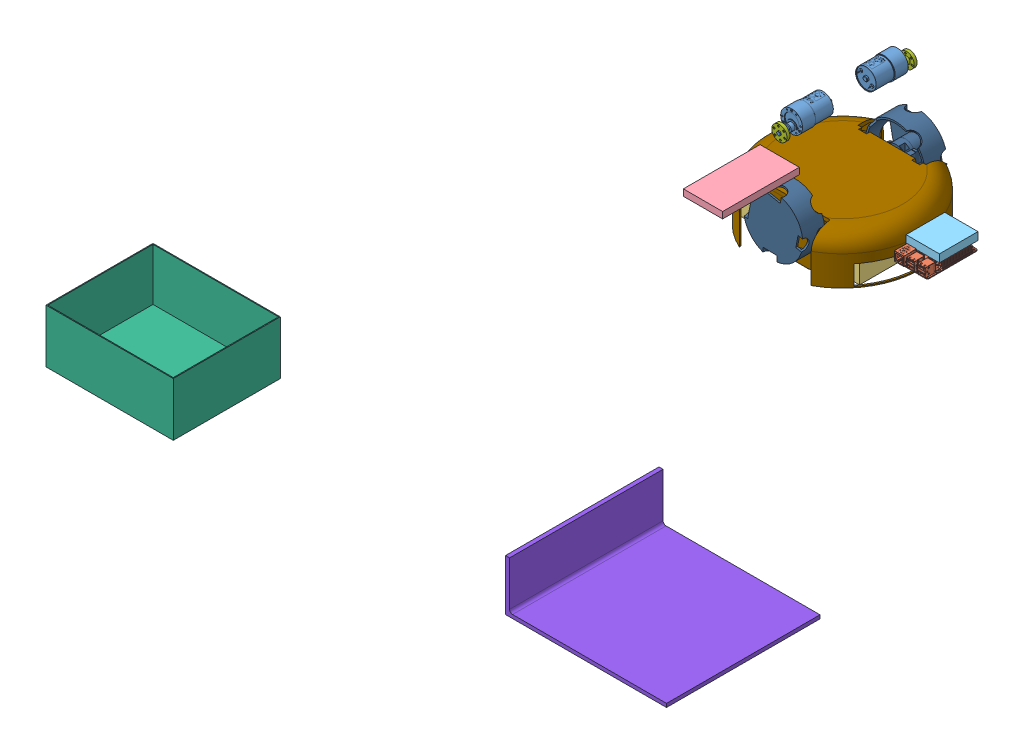
SolidWorks assembly BodyWithTwoWheels, configuration Default. Lengths in mm.
Overall size (403.59 568.25 671.49).
14 component instances, 11 part files, 40 mates.
Components (placement in the parent):
- Pololu37DGearMotor-1: Pololu37DGearMotor [Default] at (447.441 204.2914 -2152.886) x (-0.999996 0 -0.002819) z (0.002819 0 -0.999996) size (36.8 36.8 107.9)
- Pololu37DGearMotor-2: Pololu37DGearMotor [Default] at (407.2033 204.2906 -2015.4893) x (0.999996 0.000041 0.002819) z (-0.002819 0 0.999996) size (36.8 36.8 107.9)
- Part2-1: Part2 [Default] at origin
- RaspberryPi3-1: RaspberryPi3 [Default] at (547.1348 10.1 -2110.1682) x (0 0 1) z (0 1 0) size (89.64 57.31 18.92) (hidden)
- MaxoakPowerBank-1: MaxoakPowerBank [Default] at (285.8411 -26.3523 -2179.9603) x (0 0 1) z (-1 0 0) size (135 33 206)
- MotoX-1: MotoX [Default] at (449.4488 208.455 -1791.0614) size (66.04 10.84 128.96)
- AdafruitMotorHat-1: AdafruitMotorHat [Default] at (577.5455 37.34 -2158.6101) x (0 0 1) z (1 0 0) size (65 13 56)
- Cover-1: Cover [Default] at (-302.6975 -256.127 -1471.0702) size (214.11 90 180) (hidden)
- PololuHub-2: PololuHub [Default] at (427.6231 197.2914 -2190.867) x (-0.300116 -0.953902 -0.000846) z (-0.002819 0 0.999996) size (25.4 25.4 9.2)
- PololuHub-4: PololuHub [Default] at (427.0216 197.2915 -1977.5083) x (-0.982384 -0.186853 -0.002769) z (0.002819 0 -0.999996) size (25.4 25.4 9.2)
- ChargingDock-2: ChargingDock [Default] at (617.2638 -345.5594 -1823.1653) size (270.89 86 258.22)
- ChassisTwoWheels2-1: ChassisTwoWheels2 [Default] at (222.7987 26.0824 -2119.2295) x (0.999996 0 0.002819) z (-0.002819 0 0.999996) size (298.04 128.63 268.43)
- WheelWithHolesPETG3-1: WheelWithHolesPETG3 [Default] at (393.0863 33.0824 -2220.9926) x (0.999992 0.002819 0.002819) z (0.002819 -0.999996 0.000008) size (109.89 62.88 109.89)
- WheelWithHolesPETG3-2: WheelWithHolesPETG3 [Default] at (392.5171 33.0824 -2019.065) x (0.999992 -0.002819 0.002819) z (0.002819 0.999996 0.000008) size (109.89 62.88 109.89)
Mates (geometry in assembly coordinates):
- Coincident2: coincident anti-aligned: line of Pololu37DGearMotor-1 through (427.5723 197.2914 -2172.8671) axis (0.002819 0 -0.999996); line of Pololu37DGearMotor-2 through (427.0723 197.2914 -1995.5082) axis (-0.002819 0 0.999996)
- Coincident8: coincident anti-aligned: line of ? through (582.8805 17.575 -2172.7936) axis (0 0 -1); line of ? through (582.8805 17.575 -2018.7936) axis (0 0 1)
- Coincident9: coincident aligned: line of ? through (582.8805 24.575 -2118.4936) axis (0 0 1); line of ? through (582.8805 24.575 -2095.7936) axis (0 0 1)
- Coincident10: coincident anti-aligned: line of ? through (582.8805 24.575 -2073.0936) axis (0 0 -1); line of ? through (582.8805 24.575 -2095.7936) axis (0 0 1)
- Coincident11: coincident aligned: line of Pololu37DGearMotor-1 through (430.042 24.575 -2118.4936) axis (0 0 1); line of ? through (430.042 24.575 -2095.7936) axis (0 0 1)
- Coincident12: coincident anti-aligned: line of Pololu37DGearMotor-2 through (430.042 24.575 -2073.0936) axis (0 0 -1); line of ? through (430.042 24.575 -2095.7936) axis (0 0 1)
- Distance1: distance = 27.57 mm anti-aligned: plane of RaspberryPi3-1 through (577.5455 9.77 -2073.686) normal (0 -1 0); plane of AdafruitMotorHat-1 through (577.5455 37.34 -2158.6101) normal (0 1 0)
- Coincident17: coincident aligned: plane of RaspberryPi3-1 through (577.5455 9.34 -2076.676) normal (1 0 0); plane of AdafruitMotorHat-1 through (577.5455 24.34 -2158.6101) normal (1 0 0)
- Coincident18: coincident aligned: plane of RaspberryPi3-1 through (574.5555 9.34 -2158.6101) normal (0 0 -1); plane of AdafruitMotorHat-1 through (577.5455 24.34 -2158.6101) normal (0 0 -1)
- Parallel4: parallel aligned: plane of MaxoakPowerBank-1 through (491.8411 6.6477 -2179.9603) normal (1 0 0); plane of assembly through (0 0 0) normal (1 0 0)
- Parallel5: parallel anti-aligned: plane of ? through (600.042 24.575 -2175.7936) normal (0 0 -1); plane of assembly through (0 0 0) normal (0 0 1)
- Coincident33: coincident: point of ?; line of ? through (582.8805 17.575 -2095.7936) axis (0 0 1)
- Coincident34: coincident anti-aligned: line of Pololu37DGearMotor-1 through (427.5723 197.2914 -2172.8671) axis (0.002819 0 -0.999996); line of PololuHub-2 through (427.648 197.2914 -2199.7169) axis (-0.002819 0 0.999996)
- Coincident35: coincident anti-aligned: line of Pololu37DGearMotor-2 through (427.0723 197.2914 -1995.5082) axis (-0.002819 0 0.999996); line of PololuHub-4 through (426.9967 197.2914 -1968.6583) axis (0.002819 0 -0.999996)
- Coincident36: coincident anti-aligned: line of ? through (582.8805 17.575 -2018.7936) axis (0 0 1); line of ? through (582.8805 17.575 -1991.9436) axis (0 0 -1)
- Coincident38: coincident anti-aligned: plane of ? through (515.042 0 -2095.7936) normal (0 -1 0); plane of assembly through (0 0 0) normal (0 1 0)
- Coincident39: coincident anti-aligned: line of ? through (582.8805 17.575 -2194.7936) axis (0 0 -1); line of ? through (582.8805 17.575 -2199.6436) axis (0 0 1)
- Parallel6: parallel aligned: plane of Pololu37DGearMotor-1; plane of assembly through (0 0 0) normal (0 1 0)
- Coincident41: coincident anti-aligned: plane of ? through (582.8805 24.575 -2172.7936) normal (0 0 -1); plane of ? through (582.8805 24.575 -2172.7936) normal (0 0 1)
- Coincident42: coincident anti-aligned: plane of ? through (582.8805 24.575 -2018.7936) normal (0 0 1); plane of ? through (582.8805 24.575 -2018.7936) normal (0 0 -1)
- Coincident43: coincident anti-aligned: plane of Pololu37DGearMotor-1; plane of ? through (430.042 24.575 -2172.7936) normal (0 0 1)
- Coincident44: coincident anti-aligned: plane of Pololu37DGearMotor-2; plane of ? through (430.042 24.575 -2018.7936) normal (0 0 -1)
- Distance3: distance = 1.5 mm aligned: plane of ? through (582.8805 17.575 -1998.2936) normal (0 0 1); plane of ? through (582.8805 17.575 -1996.7936) normal (0 0 1)
- Distance4: distance = 1.5 mm aligned: plane of PololuHub-4 through (427.0146 197.2914 -1975.0083) normal (-0.002819 0 0.999996); plane of Pololu37DGearMotor-2 through (427.0103 197.2914 -1973.5083) normal (-0.002819 0 0.999996)
- Distance5: distance = 1.5 mm aligned: plane of ? through (582.8805 17.575 -2193.2936) normal (0 0 -1); plane of ? through (582.8805 17.575 -2194.7936) normal (0 0 -1)
- Distance6: distance = 1.5 mm aligned: plane of PololuHub-2 through (427.6301 197.2914 -2193.367) normal (0.002819 0 -0.999996); plane of Pololu37DGearMotor-1 through (427.6343 197.2914 -2194.867) normal (0.002819 0 -0.999996)
- Perpendicular1: perpendicular: plane of ? through (582.8805 19.975 -2182.7936) normal (0 1 0); line of ? through (582.8805 29.925 -2186.1936) axis (0 -1 0)
- Parallel11: parallel: plane of ? through (582.8805 19.975 -2182.7936) normal (0 1 0); line of ? through (592.4105 17.575 -2216.1536) axis (-1 0 0)
- Coincident54: coincident anti-aligned: plane of ? through (582.8805 17.575 -2193.2936) normal (0 0 -1); plane of ? through (582.8805 17.575 -2193.2936) normal (0 0 1)
- Concentric1: concentric anti-aligned: cylinder of ? through (582.8805 17.575 -2188.2936) axis (0 0 -1) radius 12.7; cylinder of ? through (582.8805 17.575 -2195.2936) axis (0 0 1) radius 3.2
- Concentric2: concentric aligned: circle of ?; cylinder of ? through (587.6455 9.3218 -2187.6736) axis (0 0 -1) radius 1.335
- Coincident55: coincident anti-aligned: plane of ? through (587.6455 9.3218 -2206.1536) normal (0 0 -1); plane of ? through (587.6455 9.3218 -2206.1536) normal (0 0 1)
- Concentric3: concentric anti-aligned: cylinder of ? through (582.8805 17.575 -2012.2936) axis (0 0 -1) radius 6; cylinder of ? through (582.8805 17.575 -1907.5253) axis (0 0 1) radius 3.2
- Tangent1: tangent anti-aligned: cylinder of ? through (586.4845 1.0178 -1974.7619) axis (0 0 -1) radius 50; plane of ChargingDock-2 through (621.4227 -48.9822 -2210.9825) normal (0 1 0)
- Parallel12: parallel aligned: plane of ChargingDock-2 through (617.2638 -339.5594 -1823.1653) normal (0 1 0); plane of assembly through (0 0 0) normal (0 1 0)
- Coincident56: coincident anti-aligned: plane of RaspberryPi3-1 through (574.9874 8 -2148.344) normal (0 -1 0); plane of ? through (515.042 8 -2095.7936) normal (0 1 0)
- Concentric5: concentric aligned: cylinder of RaspberryPi3-1 through (574.0455 11.1 -2097.1101) axis (0 1 0) radius 3; cylinder of ? through (574.0455 -2 -2097.1101) axis (0 1 0) radius 1.1452
- Concentric6: concentric anti-aligned: cylinder of ? through (600.042 17.575 -2047.2936) axis (0 0 1) radius 7.5; cylinder of ? through (600.042 17.575 -1972.8894) axis (0 0 -1) radius 6.523
- Concentric8: concentric anti-aligned: circle of ChassisTwoWheels2-1; cylinder of WheelWithHolesPETG3-1 through (393.0853 33.0824 -2220.6526) axis (-0.002819 0 0.999996) radius 3.4
- Concentric9: concentric anti-aligned: circle of ChassisTwoWheels2-1; cylinder of WheelWithHolesPETG3-2 through (392.518 33.0824 -2019.405) axis (0.002819 0 -0.999996) radius 3.4
